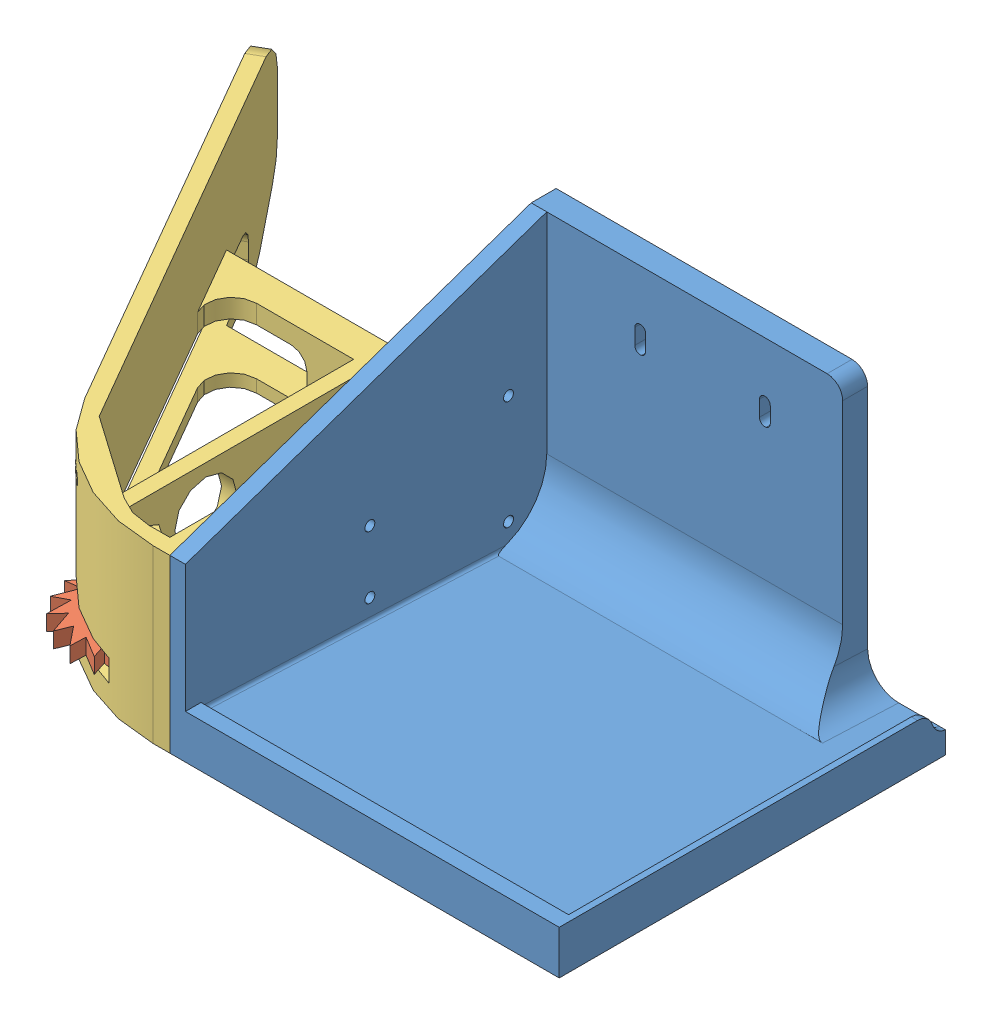
SolidWorks assembly Weight holder, configuration Default. Lengths in mm.
Overall size (257.5 95 168.62).
3 component instances, 3 part files, 5 mates.
Components (placement in the parent):
- 3D Guifderail right - part1-1: 3D Guifderail right - part1 [Default] at (-89.1659 -71.7957 92.5129) size (125 95 124)
- spiked gear-1: spiked gear [Default] at (-121.9342 -64.4295 71.0933) x (0.532429 0 -0.846475) z (0 1 0) size (39.39 40 10)
- 3D_Guifderail_right_-_frontv2-1: 3D_Guifderail_right_-_frontv2 [Default] at (-89.1659 -71.7957 92.5129) x (-1 0 0) z (0 0 -1) size (132.5 55 162.71)
Mates (geometry in assembly coordinates):
- Coincident7: coincident: plane of 3D Guifderail right - part1-1 through (-89.1659 -61.7957 87.5129) normal (-1 0 0); plane of 3D_Guifderail_right_-_frontv2-1 through (-89.1659 -16.7957 92.5129) normal (1 0 0)
- Coincident8: coincident: plane of 3D Guifderail right - part1-1 through (-89.1659 -71.7957 92.5129) normal (0 -1 0); plane of 3D_Guifderail_right_-_frontv2-1 through (-89.1659 -71.7957 92.5129) normal (0 -1 0)
- Coincident9: coincident: plane of 3D Guifderail right - part1-1 through (-89.1659 -16.7957 92.5129) normal (0 0 1); plane of 3D_Guifderail_right_-_frontv2-1 through (-89.1659 -16.7957 92.5129) normal (0 0 1)
- Coincident10: coincident: plane of spiked gear-1 through (-121.9342 -64.4295 71.0933) normal (0 -1 0); plane of 3D_Guifderail_right_-_frontv2-1 through (-96.9762 -64.4295 70.3185) normal (0 1 0)
- Concentric1: concentric: circle of spiked gear-1; circle of 3D_Guifderail_right_-_frontv2-1
